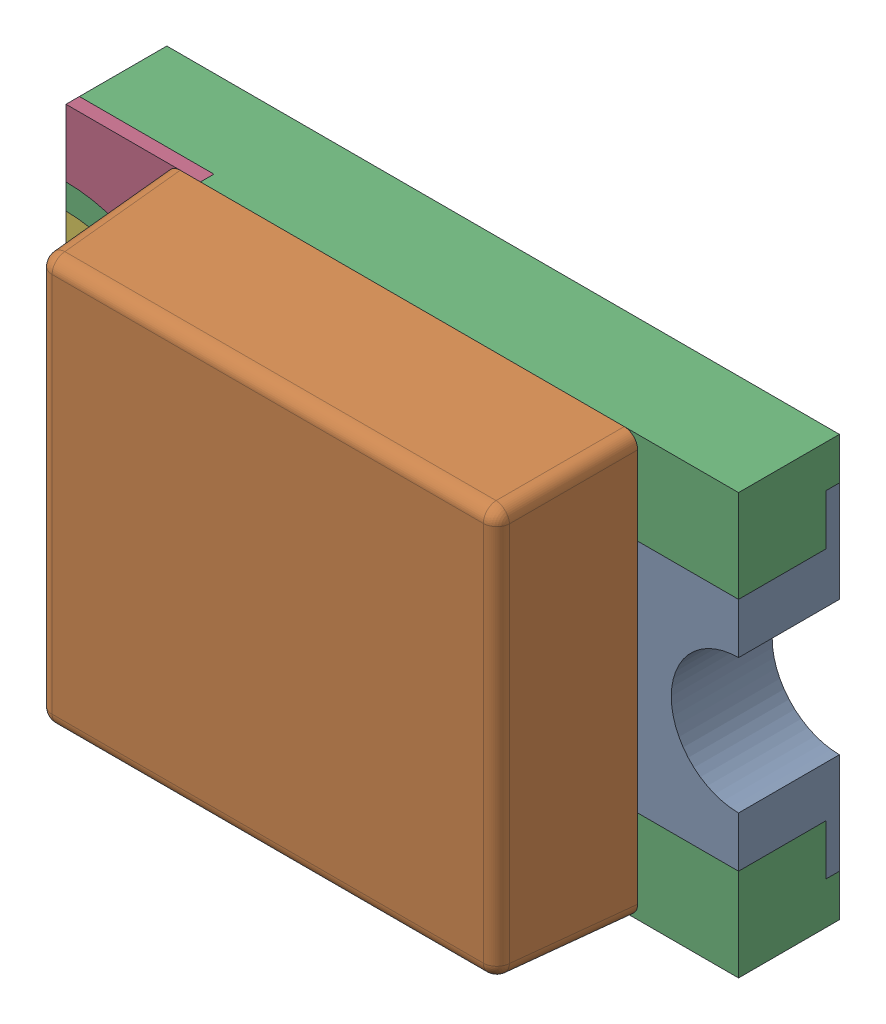
SolidWorks assembly WL-SMCW_0805_LED, configuration Standard. Lengths in mm.
Overall size (2 1.25 0.7).
6 component instances, 5 part files, 0 mates.
Components (placement in the parent):
- base-1: base [Standard] at (0.8 0 0) x (-1 0 0) z (0 0 1) size (0.4 1 0.3)
- cover-1: cover [Standard] at (0 0 0.3) size (1.4 1.25 0.4)
- housing_3-1: housing_3 [Standard] at origin size (2 1.25 0.3)
- marking-1: marking [Standard] at (-0.8 0.525 0.26) size (0.4 0.48 0.04)
- marking-2: marking [Standard] at (-0.8 -0.525 0.3) x (1 0 0) z (0 0 -1) size (0.4 0.48 0.04)
- base_2-1: base_2 [Standard] at (-0.8 0 0) size (0.4 1 0.3)
